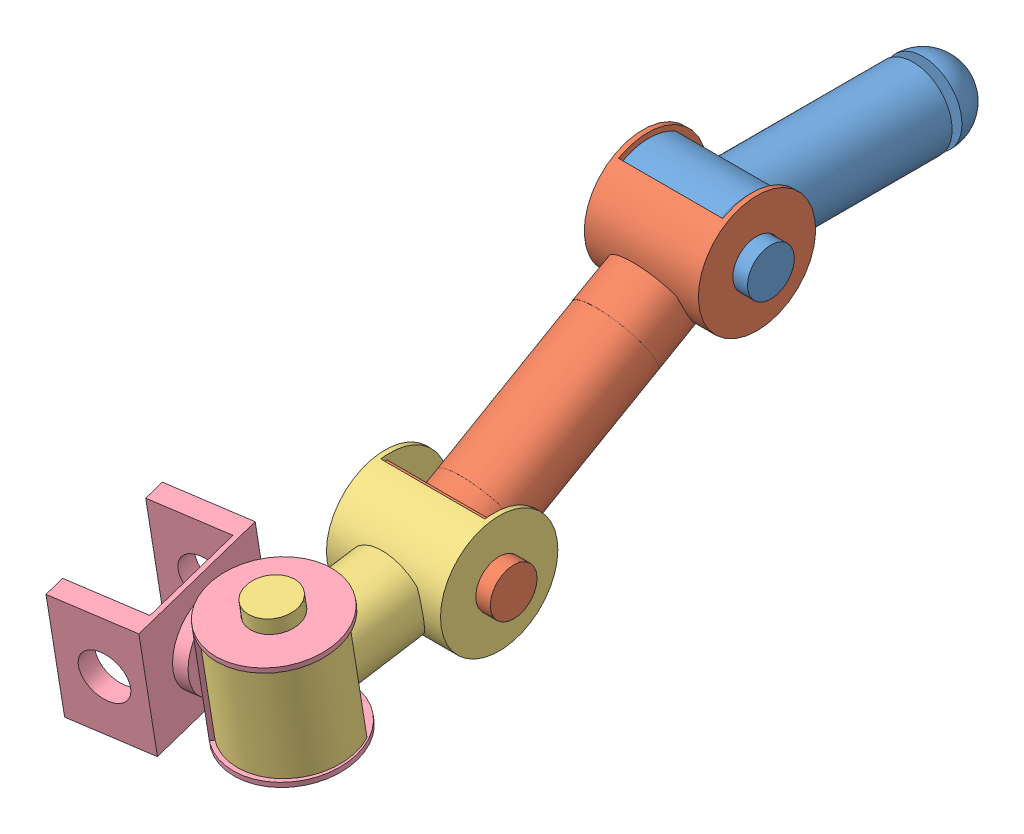
SolidWorks assembly legright, configuration Default. Lengths in mm.
Overall size (118.05 170.84 396.74).
4 component instances, 4 part files, 6 mates.
Components (placement in the parent):
- Part1-1: Part1 [Default] at (-55.9435 85.7723 123.5115) size (73.34 55.31 161.39)
- Part2-1: Part2 [Default] at (-85.1535 85.7723 237.698) x (0 -0.866614 -0.498979) z (0 -0.498979 0.866614) size (60.1 73.34 210.23)
- Part3-1: Part3 [Default] at (-85.1535 9.734 369.7595) x (0 -0.987296 -0.158895) z (0 -0.158895 0.987296) size (73.34 58.42 140.58)
- Part4-1: Part4 [Default] at (-55.9435 -32.2418 446.7446) x (0.127933 -0.157589 0.979183) z (-0.991783 -0.020328 0.126307) size (70 60 107.59)
Mates (geometry in assembly coordinates):
- Concentric1: concentric anti-aligned: cylinder of Part1-1 through (-92.6135 85.7723 237.698) axis (1 0 0) radius 12; cylinder of Part2-1 through (-82.6135 85.7723 237.698) axis (-1 0 0) radius 12
- Coincident1: coincident anti-aligned: plane of Part1-1 through (-82.6135 85.5313 237.1915) normal (-1 0 0); plane of Part2-1 through (-82.6135 85.7723 237.698) normal (1 0 0)
- Concentric3: concentric anti-aligned: cylinder of Part2-1 through (-92.6135 9.734 369.7595) axis (1 0 0) radius 12; cylinder of Part3-1 through (-82.6135 9.734 369.7595) axis (-1 0 0) radius 12
- Coincident2: coincident anti-aligned: plane of Part2-1 through (-82.6135 10.0852 369.1495) normal (-1 0 0); plane of Part3-1 through (-82.6135 9.734 369.7595) normal (1 0 0)
- Concentric4: concentric anti-aligned: cylinder of Part3-1 through (-55.9435 -39.607 445.5593) axis (0 0.987296 0.158895) radius 12; cylinder of Part4-1 through (-55.9435 -29.7341 447.1482) axis (0 -0.987296 -0.158895) radius 12
- Coincident3: coincident anti-aligned: plane of Part3-1 through (-55.9435 -29.5763 446.1681) normal (0 -0.987296 -0.158895); plane of Part4-1 through (-55.9435 -29.7341 447.1482) normal (0 0.987296 0.158895)
